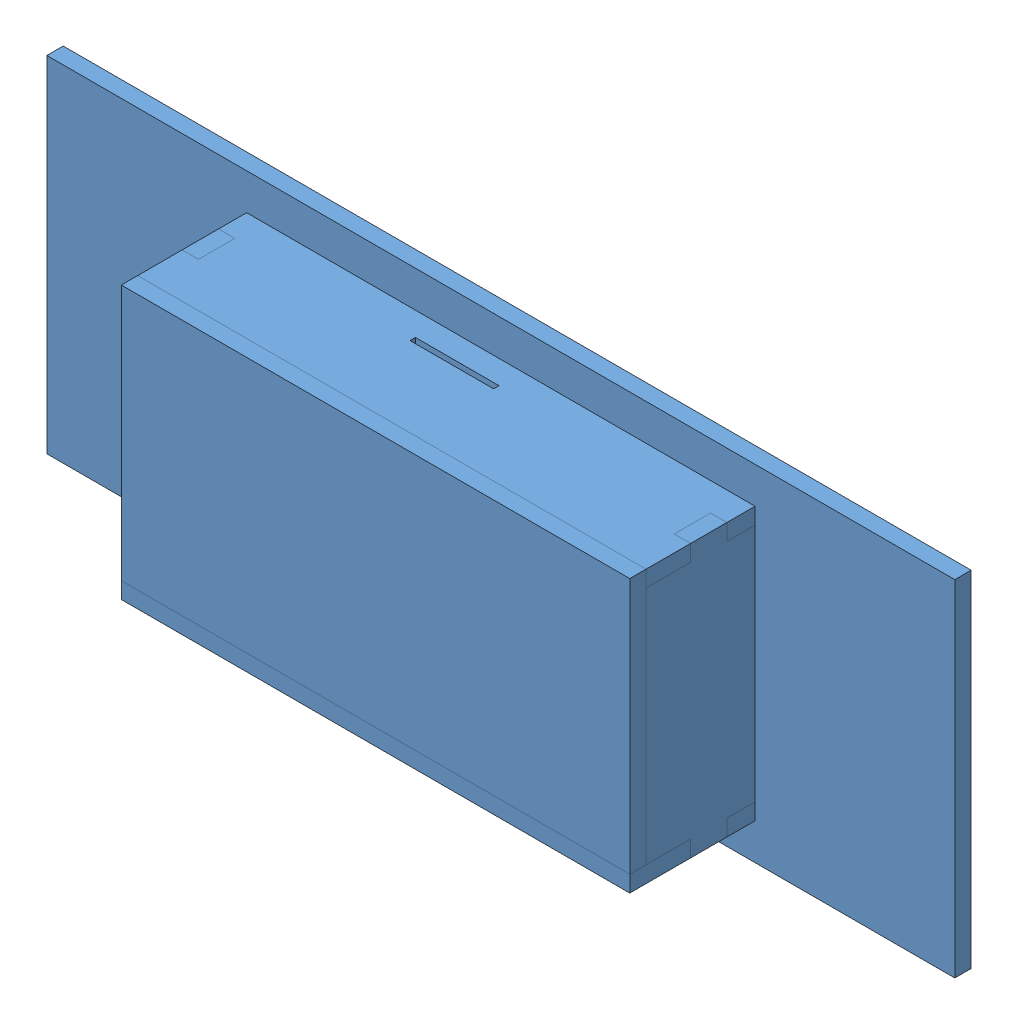
SolidWorks assembly AssemblageBoite, configuration Défaut. Lengths in mm.
Overall size (500 190 78).
11 component instances, 8 part files, 19 mates.
Components (placement in the parent):
- boitier_electronique-1: boitier_electronique [Défaut] at origin size (500 190 78)
- rouleau v1-1: rouleau v1 [Défaut] at (-11 41 31.3645) x (-1 0 0) z (0 0.924225 0.381849) size (50 30 30)
- support moteur-1: support moteur [Défaut] at (-11 41 14) x (-1 0 0) z (0 0 1) size (120 43 25)
- User Library-hp 1-100-1: User Library-hp 1-100 [Predeterminado] at (39.7 44.4976 31.5705) x (0 -1 0) z (0 0 1) size (10 43.09 12.07)
- User Library-hp 1-100-2: User Library-hp 1-100 [Predeterminado] at (-61.7 37.5024 31.5705) x (0 1 0) z (0 0 1) size (10 43.09 12.07)
- User Library-ESP32S Dev Board 0_9inch width ASSY-1: User Library-ESP32S Dev Board 0_9inch width ASSY [Default] at (17.5031 -27.4315 29) x (1 0 0) z (0 -1 0) size (25.91 13.14 49.31)
- User Library-RelaisBoard4-1: User Library-RelaisBoard4 [Défaut] at (65 56 19) x (0 -1 0) z (0 0 1) size (76.16 56 17.06)
- User Library-18650 Full-1: User Library-18650 Full [Holder X1] at (-100.6 38.3702 19) x (0 -1 0) z (0 0 1) size (77.65 20.8 25.48)
  - User Library-18650 Full_18650m-1: User Library-18650 Full_18650m [1] at (27.81 0 0) x (1 0 0) z (0 -1 0) size (77.65 21.65 20.8)
  - User Library-18650 Full_18650s-1: User Library-18650 Full_18650s [По умолчанию] at (-8.24 0 4.8249) x (0 1 0) z (1 0 0) size (6.5 20.3 3.96)
  - User Library-18650 Full_18650s-2: User Library-18650 Full_18650s [По умолчанию] at (63.86 0 4.8249) x (0 -1 0) z (-1 0 0) size (6.5 20.3 3.96)
Mates (geometry in assembly coordinates):
- Coïncidente2: coordinate: point of assembly; point of boitier_electronique-1; point of assembly
- Largeur1: width anti-aligned: plane of rouleau v1-1 through (-36 54.8634 37.0923) normal (-1 0 0); plane of support moteur-1 through (14 42.3863 31.9373) normal (1 0 0); plane of rouleau v1-1 through (-37.5 41 34) normal (1 0 0); plane of support moteur-1 through (15.5 41 34) normal (-1 0 0)
- Parallèle2: parallel aligned: plane of support moteur-1 through (15.5 41 34) normal (-1 0 0); plane of User Library-hp 1-100-1 through (16.6068 36 37.4324) normal (-1 0 0)
- Coïncidente5: coincident anti-aligned: plane of support moteur-1 through (-11 36 34) normal (0 1 0); plane of User Library-hp 1-100-1 through (24.7 36 27.5942) normal (0 -1 0)
- Coïncidente6: coincident anti-aligned: plane of support moteur-1 through (39.7 36 34) normal (-1 0 0); plane of User Library-hp 1-100-1 through (39.7 41 32.2956) normal (1 0 0)
- Tangent1: tangent anti-aligned: plane of support moteur-1 through (-11 41 24) normal (0 0 1); cylinder of User Library-hp 1-100-1 through (24.7 41 30.7162) axis (1 0 0) radius 6.7162
- Coaxiale1: concentric anti-aligned: cylinder of User Library-hp 1-100-2 through (-41.8068 41 27.1106) axis (1 0 0) radius 0.75; cylinder of User Library-hp 1-100-1 through (19.8068 41 27.1106) axis (-1 0 0) radius 0.75
- Symétrique2: symmetric aligned: plane of support moteur-1 through (-11 41 14) normal (-1 0 0); plane of User Library-hp 1-100-1 through (-38.6068 46 37.4324) normal (1 0 0); plane of User Library-hp 1-100-2 through (16.6068 36 37.4324) normal (-1 0 0)
- Coaxiale2: concentric anti-aligned: cylinder of User Library-hp 1-100-1 through (19.8068 41 36.1913) axis (-1 0 0) radius 0.75; cylinder of User Library-hp 1-100-2 through (-41.8068 41 36.1913) axis (1 0 0) radius 0.75
- Coaxiale3: concentric aligned: cylinder of rouleau v1-1 through (-11 41 31.3645) axis (1 0 0) radius 1.5; cylinder of User Library-hp 1-100-1 through (7.6068 41 31.3645) axis (1 0 0) radius 1.8
- Coïncidente11: coincident anti-aligned: plane of boitier_electronique-1 through (0 0 9) normal (0 0 1); plane of support moteur-1 through (-11 41 9) normal (0 0 -1)
- Distance2: distance = 60 mm anti-aligned: plane of boitier_electronique-1 through (-131 0 69) normal (1 0 0); plane of support moteur-1 through (-71 26 9) normal (-1 0 0)
- Distance3: distance = 10 mm anti-aligned: plane of support moteur-1 through (49 56 9) normal (0 1 0); plane of boitier_electronique-1 through (0 66 349.1446) normal (0 -1 0)
- Distance4: distance = 20 mm anti-aligned: plane of User Library-ESP32S Dev Board 0_9inch width ASSY-1 through (17.5031 -27.4315 29) normal (0 0 -1); plane of boitier_electronique-1 through (0 0 9) normal (0 0 1)
- Distance7: distance = 10 mm anti-aligned: plane of boitier_electronique-1 through (0 0 9) normal (0 0 1); plane of User Library-RelaisBoard4-1 through (68 53 19) normal (0 0 -1)
- Distance5: distance = 10 mm anti-aligned: plane of User Library-RelaisBoard4-1 through (121 -17.16 20.6) normal (1 0 0); plane of boitier_electronique-1 through (131 0 69) normal (-1 0 0)
- Distance6: distance = 10 mm anti-aligned: plane of boitier_electronique-1 through (0 66 349.1446) normal (0 -1 0); plane of User Library-RelaisBoard4-1 through (118 56 20.6) normal (0 1 0)
- Distance8: distance = 10 mm anti-aligned: plane of boitier_electronique-1 through (0 0 9) normal (0 0 1); plane of User Library-18650 Full-1/User Library-18650 Full_18650m-1 through (-111 47.2852 19) normal (0 0 -1)
- Distance9: distance = 20 mm anti-aligned: plane of User Library-18650 Full-1/User Library-18650 Full_18650m-1 through (-111 45.4852 37.61) normal (-1 0 0); plane of boitier_electronique-1 through (-131 0 69) normal (1 0 0)
